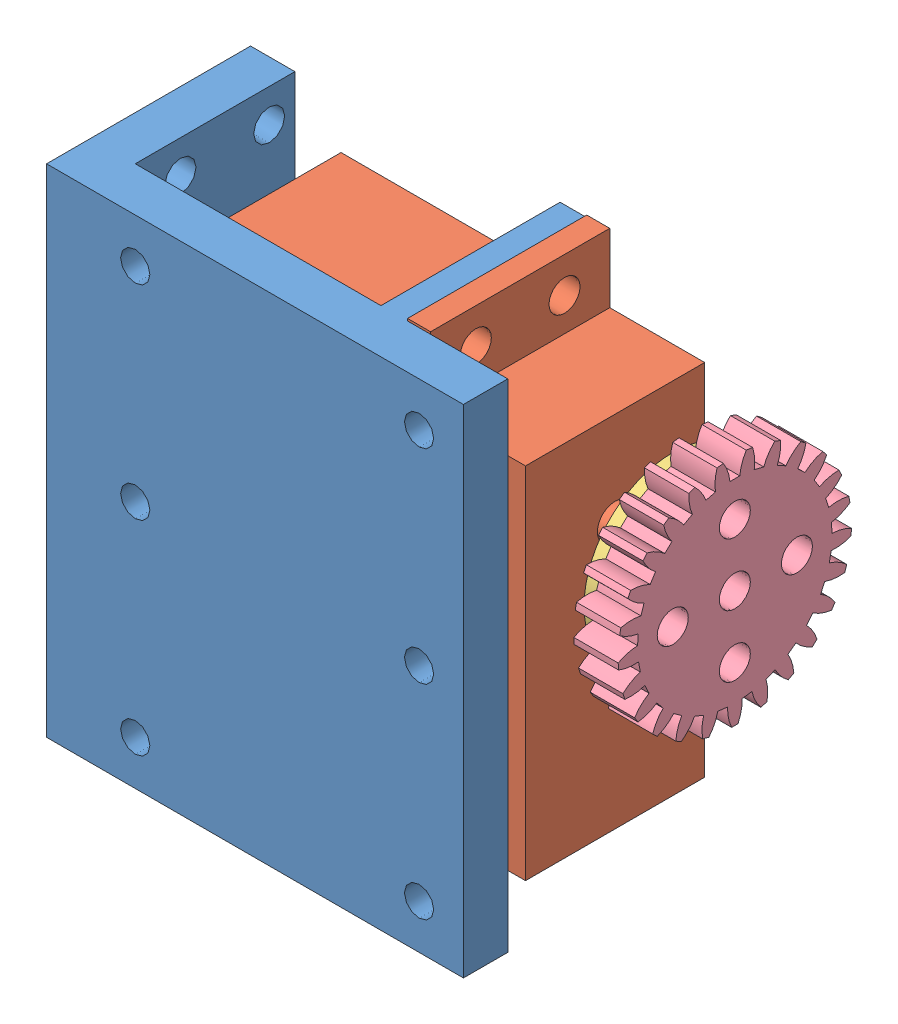
SolidWorks assembly 装配体3, configuration 默认. Lengths in mm.
Overall size (62.5 56.25 28.25).
4 component instances, 4 part files, 8 mates.
Components (placement in the parent):
- 20KG大舵机支架-1: 20KG大舵机支架 [Default] at (3.3894 4.911 63.6) size (47 56 25.2)
- 20KG大舵机-1: 20KG大舵机 [Default] at (26.3894 5.161 53.5) x (0 -1 0) z (-1 0 0) size (56 20.2 45)
- 舵盘 (1)-1: 舵盘 (1) [默认] at (34.8894 14.911 53.5) x (0 0 1) z (-1 0 0) size (20 20 4.5)
- 齿轮3-1: 齿轮3 [默认] at (39.8894 -17.7771 74.1398) x (0 0 1) z (-1 0 0) size (26.3 26.25 5)
Mates (geometry in assembly coordinates):
- 同心3: concentric aligned: cylinder of 20KG大舵机支架-1 through (-22.6106 29.161 48.5) axis (1 0 0) radius 1.75; cylinder of 20KG大舵机-1 through (13.0894 29.161 48.5) axis (1 0 0) radius 1.75
- 同心4: concentric aligned: cylinder of 20KG大舵机支架-1 through (-22.6106 29.161 58.5) axis (1 0 0) radius 1.75; cylinder of 20KG大舵机-1 through (13.0894 29.161 58.5) axis (1 0 0) radius 1.75
- 重合1: coincident anti-aligned: plane of 20KG大舵机支架-1 through (13.0894 32.911 43.4) normal (1 0 0); plane of 20KG大舵机-1 through (13.0894 5.161 53.5) normal (-1 0 0)
- 重合2: coincident anti-aligned: plane of 20KG大舵机-1 through (30.3894 14.911 53.5) normal (1 0 0); plane of 舵盘 (1)-1 through (30.3894 14.911 53.5) normal (-1 0 0)
- 同心6: concentric anti-aligned: cylinder of 20KG大舵机-1 through (30.3894 14.911 53.5) axis (1 0 0) radius 1.25; cylinder of 舵盘 (1)-1 through (38.8894 14.911 53.5) axis (-1 0 0) radius 1.65
- 同心9: concentric: cylinder of 舵盘 (1)-1 through (38.8894 14.911 53.5) axis (-1 0 0) radius 1.65; cylinder of 齿轮3-1 through (41.8894 14.911 53.5) axis (1 0 0) radius 1.75
- 同心10: concentric: cylinder of 舵盘 (1)-1 through (41.3894 21.911 53.5) axis (-1 0 0) radius 1.65; cylinder of 齿轮3-1 through (41.8894 21.911 53.5) axis (1 0 0) radius 1.75
- 重合4: coincident anti-aligned: plane of 舵盘 (1)-1 through (34.8894 14.911 53.5) normal (1 0 0); plane of 齿轮3-1 through (34.8894 17.9382 48.439) normal (-1 0 0)
